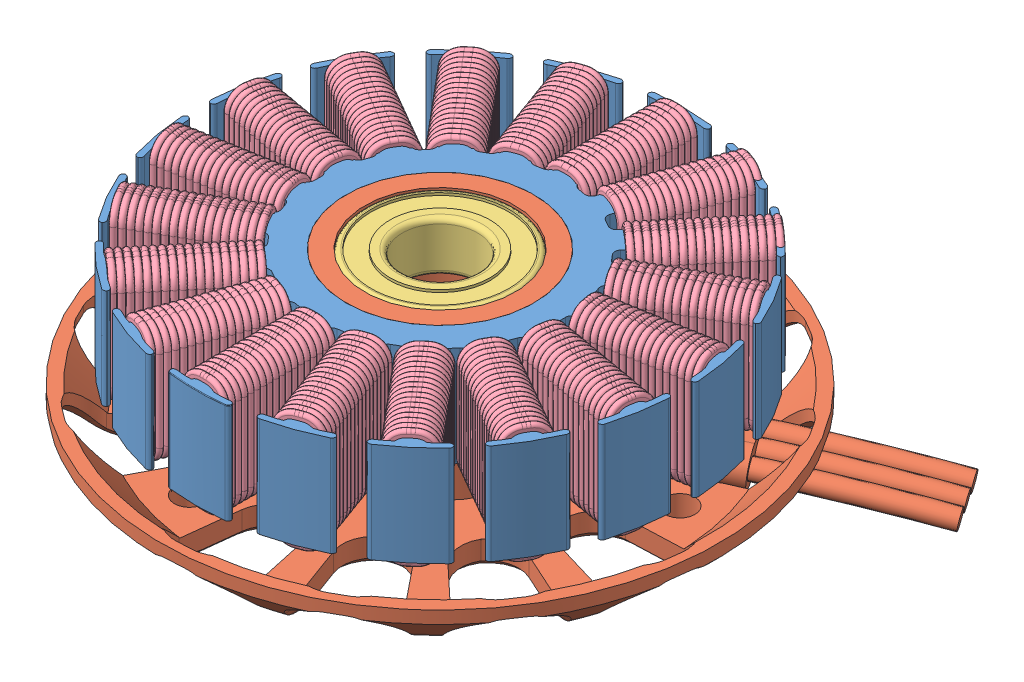
SolidWorks assembly Stator Assembly, configuration Default. Lengths in mm.
Overall size (63.83 17.22 63.8).
24 component instances, 6 part files, 66 mates.
Components (placement in the parent):
- Iron Core-1: Iron Core [Default] at origin size (38.93 8.03 39)
- Stator Base Plate-1: Stator Base Plate [Default] at (0 -9.75 0) x (0.733167 0 -0.680048) z (0.680048 0 0.733167) size (52.76 13.82 44.5)
- Bearing-1: Bearing [Default] at (0 2 0) x (0.876835 0 0.480792) z (0 -1 0) size (12 12 4)
- Bearing-2: Bearing [Default] at (0 -7.75 0) x (1 0 0) z (0 1 0) size (12 12 4)
- Motor Windings-1: Motor Windings [Default] at (-16.4024 0 9.47) x (0.5 0 0.866025) z (-0.866025 0 0.5) size (3.5 9.5 9)
- Motor Windings-2: Motor Windings [Default] at (-12.1743 0 14.5088) x (-0.766044 0 -0.642788) z (-0.642788 0 0.766044) size (3.5 9.5 9)
- Motor Windings-4: Motor Windings [Default] at (-6.4778 0 17.7977) x (-0.939693 0 -0.34202) z (-0.34202 0 0.939693) size (3.5 9.5 9)
- Motor Windings-6: Motor Windings [Default] at (0 0 18.9399) size (3.5 9.5 9)
- Motor Windings-8: Motor Windings [Default] at (6.4778 0 17.7977) x (0.939693 0 -0.34202) z (0.34202 0 0.939693) size (3.5 9.5 9)
- Motor Windings-10: Motor Windings [Default] at (12.1743 0 14.5088) x (0.766044 0 -0.642788) z (0.642788 0 0.766044) size (3.5 9.5 9)
- Motor Windings-12: Motor Windings [Default] at (16.4024 0 9.47) x (0.5 0 -0.866025) z (0.866025 0 0.5) size (3.5 9.5 9)
- Motor Windings-14: Motor Windings [Default] at (18.6522 0 3.2889) x (0.173648 0 -0.984808) z (0.984808 0 0.173648) size (3.5 9.5 9)
- Motor Windings-16: Motor Windings [Default] at (18.6522 0 -3.2889) x (-0.173648 0 -0.984808) z (0.984808 0 -0.173648) size (3.5 9.5 9)
- Motor Windings-20: Motor Windings [Default] at (16.4024 0 -9.47) x (0.5 0 0.866025) z (0.866025 0 -0.5) size (3.5 9.5 9)
- Motor Windings-26: Motor Windings [Default] at (0 0 -18.9399) x (1 0 0) z (0 0 -1) size (3.5 9.5 9)
- Motor Windings-28: Motor Windings [Default] at (-6.4778 0 -17.7977) x (0.939693 0 -0.34202) z (-0.34202 0 -0.939693) size (3.5 9.5 9)
- Motor Windings-30: Motor Windings [Default] at (-12.1743 0 -14.5088) x (0.766044 0 -0.642788) z (-0.642788 0 -0.766044) size (3.5 9.5 9)
- Motor Windings-32: Motor Windings [Default] at (-16.4024 0 -9.47) x (0.5 0 -0.866025) z (-0.866025 0 -0.5) size (3.5 9.5 9)
- Motor Windings-34: Motor Windings [Default] at (-18.6522 0 -3.2889) x (-0.173648 0 0.984808) z (-0.984808 0 -0.173648) size (3.5 9.5 9)
- Motor Windings-36: Motor Windings [Default] at (-18.6522 0 3.2889) x (0.173648 0 0.984808) z (-0.984808 0 0.173648) size (3.5 9.5 9)
- Motor Windings-39: Motor Windings [Default] at (6.7116 0 -7.9986) x (0.766044 0 0.642788) z (-0.642788 0 0.766044) size (3.5 9.5 9)
- Motor Windings-40: Motor Windings [Default] at (3.5712 0 -9.8118) x (0.939693 0 0.34202) z (-0.34202 0 0.939693) size (3.5 9.5 9)
- Retaining Washer-1: Retaining Washer [Default] at (0 -11.75 0) x (0.999968 0 -0.008017) z (0.008017 0 0.999968) size (9.07 2.5 9.07)
- M3x0.5mm-5mm Button Head Screw-1: M3x0.5mm-5mm Button Head Screw [91239A110] at (0 -12.35 0) x (0.201004 0 -0.97959) z (0 -1 0) size (5.7 5.7 6.94)
Mates (geometry in assembly coordinates):
- Coincident26: coincident: plane of Iron Core-1 through (0 -4 0) normal (0 -1 0); plane of Stator Base Plate-1 through (-5.8653 -4 5.4404) normal (0 1 0)
- Concentric2: concentric: cylinder of Stator Base Plate-1 through (0 0 0) axis (0 1 0) radius 6; cylinder of Bearing-1 through (0 0 0) axis (0 -1 0) radius 6
- Coincident27: coincident: plane of Stator Base Plate-1 through (0 0 0) normal (0 1 0); plane of Bearing-1 through (0 0 0) normal (0 -1 0)
- Concentric3: concentric: cylinder of Stator Base Plate-1 through (0 -5.75 0) axis (0 -1 0) radius 6; cylinder of Bearing-2 through (0 -5.75 0) axis (0 1 0) radius 6
- Coincident28: coincident: plane of Stator Base Plate-1 through (0 -5.75 0) normal (0 -1 0); plane of Bearing-2 through (0 -5.75 0) normal (0 1 0)
- Coincident29: coordinate: point of Iron Core-1; point of assembly
- Coincident30: coincident: plane of Iron Core-1 through (0 0 0) normal (0 0 1); plane of assembly through (0 0 0) normal (0 0 1)
- Width2: width: plane of Motor Windings-1 through (-9.2332 3.25 3.8874) normal (0.5 0 0.866025); plane of Motor Windings-1 through (-7.9832 3.25 6.0525) normal (-0.5 0 -0.866025); plane of Iron Core-1 through (-15.9317 -16.7919 10.3529) normal (0.5 0 0.866025); plane of Iron Core-1 through (-16.9317 -16.7919 8.6208) normal (-0.5 0 -0.866025)
- Coincident33: coincident: plane of Iron Core-1 through (0 0 0) normal (0 1 0); plane of Motor Windings-1 through (-16.4024 0 9.47) normal (0 1 0)
- Tangent2: tangent: cylinder of Iron Core-1 through (0 -16.7919 0) axis (0 1 0) radius 19; cylinder of Motor Windings-1 through (-16.9359 -3.25 8.0459) axis (0 1 0) radius 0.25
- Width3: width: plane of Motor Windings-2 through (-5.4317 -3.25 8.4179) normal (-0.766044 0 -0.642788); plane of Motor Windings-2 through (-7.3468 -3.25 6.8109) normal (0.766044 0 0.642788); plane of Iron Core-1 through (-12.9621 -17.1014 13.8919) normal (-0.766044 0 -0.642788); plane of Iron Core-1 through (-11.43 -17.1014 15.1775) normal (0.766044 0 0.642788)
- Coincident35: coincident: plane of Motor Windings-2 through (-12.1743 0 14.5088) normal (0 -1 0); plane of assembly through (0 0 0) normal (0 1 0)
- Tangent3: tangent: cylinder of Iron Core-1 through (0 -17.1014 0) axis (0 1 0) radius 19; cylinder of Motor Windings-2 through (-13.1627 -3.25 13.3531) axis (0 1 0) radius 0.25
- Width4: width: plane of Motor Windings-4 through (-2.225 -3.25 9.768) normal (-0.939693 0 -0.34202); plane of Motor Windings-4 through (-4.5743 -3.25 8.9129) normal (0.939693 0 0.34202); plane of Iron Core-1 through (-5.5497 -16.1888 18.1714) normal (0.939693 0 0.34202); plane of Iron Core-1 through (-7.4291 -16.1888 17.4874) normal (-0.939693 0 -0.34202)
- Coincident37: coincident: plane of Motor Windings-4 through (-6.4778 0 17.7977) normal (0 -1 0); plane of assembly through (0 0 0) normal (0 1 0)
- Tangent4: tangent: cylinder of Iron Core-1 through (0 -16.1888 0) axis (0 1 0) radius 19; cylinder of Motor Windings-4 through (-7.8019 -3.25 17.0497) axis (0 1 0) radius 0.25
- Width5: width: plane of Motor Windings-6 through (-1.25 3.25 9.9399) normal (1 0 0); plane of Motor Windings-6 through (1.25 3.25 9.9399) normal (-1 0 0); plane of Iron Core-1 through (1 -15.0031 18.9737) normal (1 0 0); plane of Iron Core-1 through (-1 -15.0031 18.9737) normal (-1 0 0)
- Coincident39: coincident: plane of Motor Windings-6 through (0 0 18.9399) normal (0 1 0); plane of assembly through (0 0 0) normal (0 1 0)
- Tangent5: tangent: cylinder of Iron Core-1 through (0 -15.0031 0) axis (0 1 0) radius 19; cylinder of Motor Windings-6 through (-1.5 -3.25 18.6899) axis (0 1 0) radius 0.25
- Width6: width: plane of Motor Windings-8 through (2.225 3.25 9.768) normal (0.939693 0 -0.34202); plane of Motor Windings-8 through (4.5743 3.25 8.9129) normal (-0.939693 0 0.34202); plane of Iron Core-1 through (7.4291 -16.1888 17.4874) normal (0.939693 0 -0.34202); plane of Iron Core-1 through (5.5497 -16.1888 18.1714) normal (-0.939693 0 0.34202)
- Coincident41: coincident: plane of Motor Windings-8 through (6.4778 0 17.7977) normal (0 1 0); plane of assembly through (0 0 0) normal (0 1 0)
- Tangent6: tangent: cylinder of Iron Core-1 through (0 -16.1888 0) axis (0 1 0) radius 19; cylinder of Motor Windings-8 through (4.9828 -3.25 18.0758) axis (0 1 0) radius 0.25
- Width7: width: plane of Motor Windings-10 through (5.4317 3.25 8.4179) normal (0.766044 0 -0.642788); plane of Motor Windings-10 through (7.3468 3.25 6.8109) normal (-0.766044 0 0.642788); plane of Iron Core-1 through (12.9621 -17.1014 13.8919) normal (0.766044 0 -0.642788); plane of Iron Core-1 through (11.43 -17.1014 15.1775) normal (-0.766044 0 0.642788)
- Coincident43: coincident: plane of Motor Windings-10 through (12.1743 0 14.5088) normal (0 1 0); plane of assembly through (0 0 0) normal (0 1 0)
- Tangent7: tangent: cylinder of Iron Core-1 through (0 -17.1014 0) axis (0 1 0) radius 19; cylinder of Motor Windings-10 through (10.8646 -3.25 15.2815) axis (0 1 0) radius 0.25
- Width8: width: plane of Motor Windings-12 through (7.9832 3.25 6.0525) normal (0.5 0 -0.866025); plane of Motor Windings-12 through (9.2332 3.25 3.8874) normal (-0.5 0 0.866025); plane of Iron Core-1 through (16.9317 -16.7919 8.6208) normal (0.5 0 -0.866025); plane of Iron Core-1 through (15.9317 -16.7919 10.3529) normal (-0.5 0 0.866025)
- Coincident45: coincident: plane of Motor Windings-12 through (16.4024 0 9.47) normal (0 1 0); plane of assembly through (0 0 0) normal (0 1 0)
- Tangent8: tangent: cylinder of Motor Windings-12 through (15.4359 -3.25 10.644) axis (0 1 0) radius 0.25; cylinder of Iron Core-1 through (0 -16.7919 0) axis (0 1 0) radius 19
- Width9: width: plane of Motor Windings-14 through (9.5718 3.25 2.9571) normal (0.173648 0 -0.984808); plane of Motor Windings-14 through (10.006 3.25 0.495) normal (-0.173648 0 0.984808); plane of Iron Core-1 through (18.8591 -15.3256 2.3099) normal (0.173648 0 -0.984808); plane of Iron Core-1 through (18.5118 -15.3256 4.2796) normal (-0.173648 0 0.984808)
- Coincident47: coincident: plane of Motor Windings-14 through (18.6522 0 3.2889) normal (0 1 0); plane of assembly through (0 0 0) normal (0 1 0)
- Tangent9: tangent: cylinder of Iron Core-1 through (0 -15.3256 0) axis (0 1 0) radius 19; cylinder of Motor Windings-14 through (18.1455 -3.25 4.7227) axis (0 1 0) radius 0.25
- Width10: width: plane of Motor Windings-16 through (10.006 3.25 -0.495) normal (-0.173648 0 -0.984808); plane of Motor Windings-16 through (9.5718 3.25 -2.9571) normal (0.173648 0 0.984808); plane of Iron Core-1 through (18.5118 -15.3256 -4.2796) normal (-0.173648 0 -0.984808); plane of Iron Core-1 through (18.8591 -15.3256 -2.3099) normal (0.173648 0 0.984808)
- Coincident49: coincident: plane of Motor Windings-16 through (18.6522 0 -3.2889) normal (0 1 0); plane of assembly through (0 0 0) normal (0 1 0)
- Tangent10: tangent: cylinder of Iron Core-1 through (0 -15.3256 0) axis (0 1 0) radius 19; cylinder of Motor Windings-16 through (18.6664 -3.25 -1.7683) axis (0 1 0) radius 0.25
- Width12: width: plane of Motor Windings-20 through (7.9832 -3.25 -6.0525) normal (0.5 0 0.866025); plane of Motor Windings-20 through (9.2332 -3.25 -3.8874) normal (-0.5 0 -0.866025); plane of Iron Core-1 through (15.9317 -16.7919 -10.3529) normal (-0.5 0 -0.866025); plane of Iron Core-1 through (16.9317 -16.7919 -8.6208) normal (0.5 0 0.866025)
- Coincident53: coincident: plane of Motor Windings-20 through (16.4024 0 -9.47) normal (0 -1 0); plane of assembly through (0 0 0) normal (0 1 0)
- Tangent11: tangent: cylinder of Iron Core-1 through (0 -16.7919 0) axis (0 1 0) radius 19; cylinder of Motor Windings-20 through (16.9359 -3.25 -8.0459) axis (0 1 0) radius 0.25
- Width15: width: plane of Motor Windings-26 through (-1.25 -3.25 -9.9399) normal (1 0 0); plane of Motor Windings-26 through (1.25 -3.25 -9.9399) normal (-1 0 0); plane of Iron Core-1 through (-1 -15.0031 -18.9737) normal (-1 0 0); plane of Iron Core-1 through (1 -15.0031 -18.9737) normal (1 0 0)
- Coincident59: coincident: plane of Motor Windings-26 through (0 0 -18.9399) normal (0 -1 0); plane of assembly through (0 0 0) normal (0 1 0)
- Tangent12: tangent: cylinder of Iron Core-1 through (0 -15.0031 0) axis (0 1 0) radius 19; cylinder of Motor Windings-26 through (1.5 -3.25 -18.6899) axis (0 1 0) radius 0.25
- Width16: width: plane of Motor Windings-28 through (-4.5743 -3.25 -8.9129) normal (0.939693 0 -0.34202); plane of Motor Windings-28 through (-2.225 -3.25 -9.768) normal (-0.939693 0 0.34202); plane of Iron Core-1 through (-7.4291 -16.1888 -17.4874) normal (-0.939693 0 0.34202); plane of Iron Core-1 through (-5.5497 -16.1888 -18.1714) normal (0.939693 0 -0.34202)
- Coincident61: coincident: plane of Motor Windings-28 through (-6.4778 0 -17.7977) normal (0 -1 0); plane of assembly through (0 0 0) normal (0 1 0)
- Tangent13: tangent: cylinder of Iron Core-1 through (0 -16.1888 0) axis (0 1 0) radius 19; cylinder of Motor Windings-28 through (-4.9828 -3.25 -18.0758) axis (0 1 0) radius 0.25
- Width17: width: plane of Motor Windings-30 through (-7.3468 -3.25 -6.8109) normal (0.766044 0 -0.642788); plane of Motor Windings-30 through (-5.4317 -3.25 -8.4179) normal (-0.766044 0 0.642788); plane of Iron Core-1 through (-12.9621 -17.1014 -13.8919) normal (-0.766044 0 0.642788); plane of Iron Core-1 through (-11.43 -17.1014 -15.1775) normal (0.766044 0 -0.642788)
- Coincident63: coincident: plane of Motor Windings-30 through (-12.1743 0 -14.5088) normal (0 -1 0); plane of assembly through (0 0 0) normal (0 1 0)
- Tangent14: tangent: cylinder of Iron Core-1 through (0 -17.1014 0) axis (0 1 0) radius 19; cylinder of Motor Windings-30 through (-10.8646 -3.25 -15.2815) axis (0 1 0) radius 0.25
- Width18: width: plane of Motor Windings-32 through (-9.2332 -3.25 -3.8874) normal (0.5 0 -0.866025); plane of Motor Windings-32 through (-7.9832 -3.25 -6.0525) normal (-0.5 0 0.866025); plane of Iron Core-1 through (-16.9317 -16.7919 -8.6208) normal (-0.5 0 0.866025); plane of Iron Core-1 through (-15.9317 -16.7919 -10.3529) normal (0.5 0 -0.866025)
- Coincident65: coincident: plane of Motor Windings-32 through (-16.4024 0 -9.47) normal (0 -1 0); plane of assembly through (0 0 0) normal (0 1 0)
- Tangent15: tangent: cylinder of Iron Core-1 through (0 -16.7919 0) axis (0 1 0) radius 19; cylinder of Motor Windings-32 through (-15.4359 -3.25 -10.644) axis (0 1 0) radius 0.25
- Width19: width: plane of Motor Windings-34 through (-9.5718 3.25 -2.9571) normal (-0.173648 0 0.984808); plane of Motor Windings-34 through (-10.006 3.25 -0.495) normal (0.173648 0 -0.984808); plane of Iron Core-1 through (-18.8591 -15.3256 -2.3099) normal (-0.173648 0 0.984808); plane of Iron Core-1 through (-18.5118 -15.3256 -4.2796) normal (0.173648 0 -0.984808)
- Coincident67: coincident: plane of Motor Windings-34 through (-18.6522 0 -3.2889) normal (0 1 0); plane of assembly through (0 0 0) normal (0 1 0)
- Tangent16: tangent: cylinder of Iron Core-1 through (0 -15.3256 0) axis (0 1 0) radius 19; cylinder of Motor Windings-34 through (-18.1455 -3.25 -4.7227) axis (0 1 0) radius 0.25
- Width20: width: plane of Motor Windings-36 through (-10.006 3.25 0.495) normal (0.173648 0 0.984808); plane of Motor Windings-36 through (-9.5718 3.25 2.9571) normal (-0.173648 0 -0.984808); plane of Iron Core-1 through (-18.5118 -15.3256 4.2796) normal (0.173648 0 0.984808); plane of Iron Core-1 through (-18.8591 -15.3256 2.3099) normal (-0.173648 0 -0.984808)
- Coincident69: coincident: plane of Motor Windings-36 through (-18.6522 0 3.2889) normal (0 1 0); plane of assembly through (0 0 0) normal (0 1 0)
- Tangent17: tangent: cylinder of Iron Core-1 through (0 -15.3256 0) axis (0 1 0) radius 19; cylinder of Motor Windings-36 through (-18.6664 -3.25 1.7683) axis (0 1 0) radius 0.25
- Width22: width: plane of Motor Windings-39 through (11.5392 3.25 -15.6965) normal (0.766044 0 0.642788); plane of Motor Windings-39 through (13.4543 3.25 -14.0895) normal (-0.766044 0 -0.642788); plane of Iron Core-1 through (11.43 -17.1014 -15.1775) normal (-0.766044 0 -0.642788); plane of Iron Core-1 through (12.9621 -17.1014 -13.8919) normal (0.766044 0 0.642788)
- Coincident73: coincident: plane of Iron Core-1 through (0 0 0) normal (0 1 0); plane of Motor Windings-39 through (6.7116 0 -7.9986) normal (0 1 0)
- Tangent18: tangent: cylinder of Iron Core-1 through (0 -17.1014 0) axis (0 1 0) radius 19; cylinder of Motor Windings-39 through (13.4851 3.25 -13.7373) axis (0 -1 0) radius 0.25
- Width23: width: plane of Motor Windings-40 through (6.9106 3.25 -22.6415) normal (0.939693 0 0.34202); plane of ? through (9.2599 3.25 -21.7865) normal (-0.939693 0 -0.34202); plane of Iron Core-1 through (5.5497 -16.1888 -18.1714) normal (-0.939693 0 -0.34202); plane of Iron Core-1 through (7.4291 -16.1888 -17.4874) normal (0.939693 0 0.34202)
- Coincident75: coincident: plane of Motor Windings-40 through (5.0071 0 -13.7568) normal (0 1 0); plane of assembly through (0 0 0) normal (0 1 0)
- Tangent19: tangent: cylinder of Iron Core-1 through (0 -16.1888 0) axis (0 1 0) radius 19; cylinder of Motor Windings-40 through (7.9734 3.25 -17.5211) axis (0 -1 0) radius 0.25
- Concentric4: concentric: cylinder of Bearing-2 through (0 -5.75 0) axis (0 -1 0) radius 3; cylinder of Retaining Washer-1 through (0 -9.25 0) axis (0 1 0) radius 3.05
- Coincident77: coincident: plane of Bearing-2 through (0 -9.75 0) normal (0 -1 0); plane of Retaining Washer-1 through (-2.9749 -9.75 0.0239) normal (0 1 0)
- Concentric5: concentric: cylinder of Iron Core-1 through (0 -4 0) axis (0 1 0) radius 7.5; cylinder of Stator Base Plate-1 through (0 4 0) axis (0 1 0) radius 7.5
- Concentric6: concentric: cylinder of Retaining Washer-1 through (0 -9.25 0) axis (0 1 0) radius 1.55; cylinder of M3x0.5mm-5mm Button Head Screw-1 through (0 -12.35 0) axis (0 -1 0) radius 2.85
- Coincident78: coincident: plane of Retaining Washer-1 through (-3.0499 -10.7 0.0245) normal (0 -1 0); plane of M3x0.5mm-5mm Button Head Screw-1 through (-2.7918 -10.7 -0.5729) normal (0 1 0)
